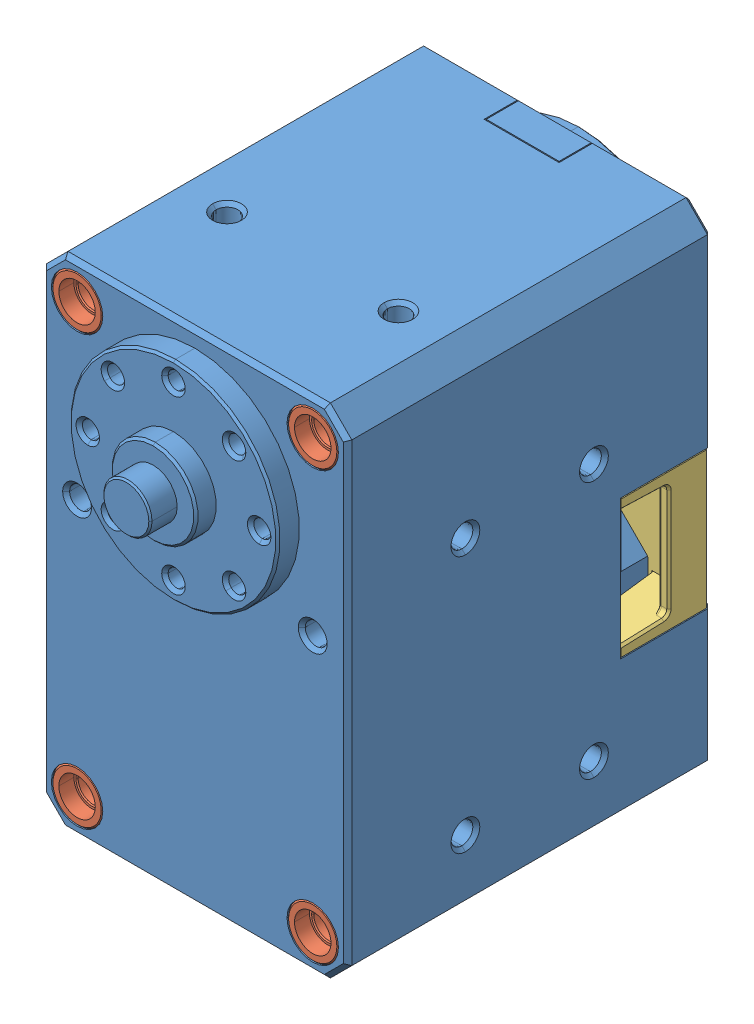
SolidWorks assembly XM430-W350, configuration Default. Lengths in mm.
Overall size (28.5 46.5 42.4).
11 component instances, 3 part files, 0 mates.
Components (placement in the parent):
- XM,H-430_idler.stp-1: XM,H-430_idler.stp [Default] at origin size (28.5 46.5 42.4)
  - X-430_IDLE.stp-1: X-430_IDLE.stp [Default] at origin size (28.5 46.5 42.4)
  - X-430_SPACER_RING.stp-1: X-430_SPACER_RING.stp [Default] at (11 8 14.2) x (-1 0 0) z (0 1 0) size (4.8 2.8 4.8)
  - X-430_SPACER_RING.stp-2: X-430_SPACER_RING.stp [Default] at (-11 8 14.2) x (-1 0 0) z (0 1 0) size (4.8 2.8 4.8)
  - X-430_SPACER_RING.stp-3: X-430_SPACER_RING.stp [Default] at (11 -32 14.2) x (-1 0 0) z (0 1 0) size (4.8 2.8 4.8)
  - X-430_SPACER_RING.stp-4: X-430_SPACER_RING.stp [Default] at (-11 -32 14.2) x (-1 0 0) z (0 1 0) size (4.8 2.8 4.8)
  - X-430_SPACER_RING.stp-5: X-430_SPACER_RING.stp [Default] at (-11 8 -14.2) x (1 0 0) z (0 1 0) size (4.8 2.8 4.8)
  - X-430_SPACER_RING.stp-6: X-430_SPACER_RING.stp [Default] at (11 8 -14.2) x (1 0 0) z (0 1 0) size (4.8 2.8 4.8)
  - X-430_SPACER_RING.stp-7: X-430_SPACER_RING.stp [Default] at (-11 -32 -14.2) x (1 0 0) z (0 1 0) size (4.8 2.8 4.8)
  - X-430_SPACER_RING.stp-8: X-430_SPACER_RING.stp [Default] at (11 -32 -14.2) x (1 0 0) z (0 1 0) size (4.8 2.8 4.8)
  - X-430_CVR_CABLE.stp-1: X-430_CVR_CABLE.stp [Default] at origin size (28.5 12.8 8.8)
